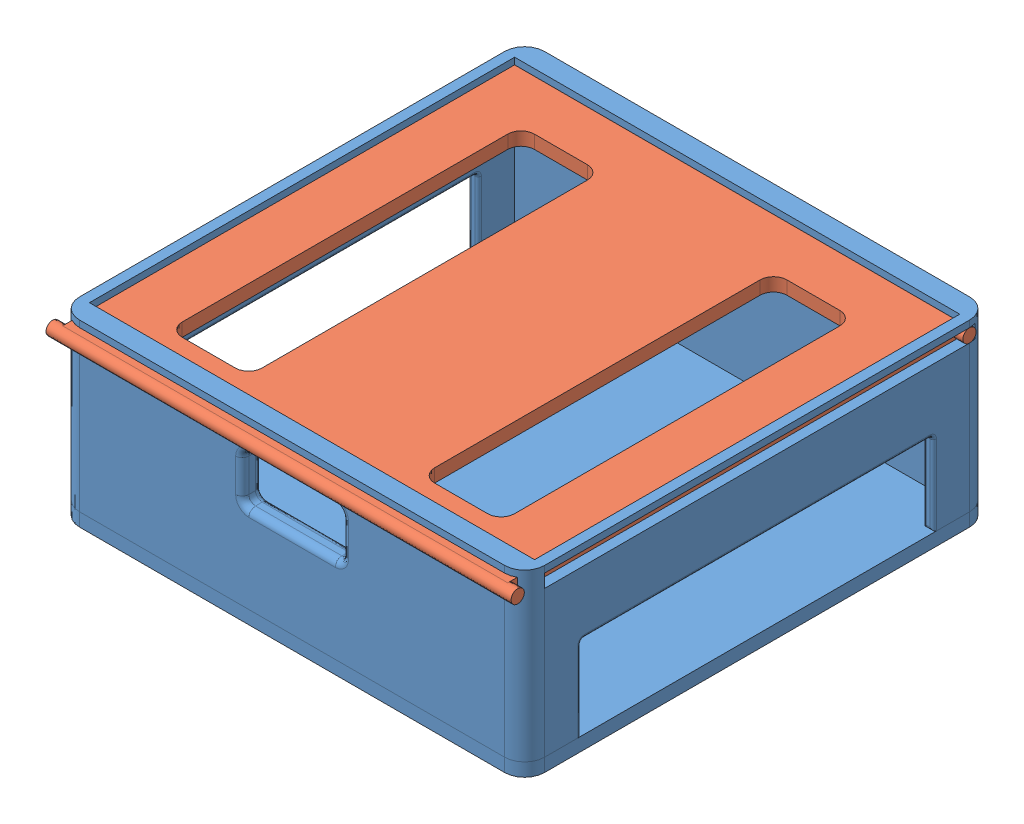
SolidWorks assembly Caja_ESP32, configuration Predeterminado. Lengths in mm.
Overall size (70 27 72.04).
2 component instances, 2 part files, 7 mates.
Components (placement in the parent):
- Caja_ESP32-1: Caja_ESP32 [Predeterminado] at (-4.1994 -8.4591 70) size (70 27 70)
- Slider-1: Slider [Predeterminado] at (-4.1994 14.5409 37.0359) size (70 2 70)
Mates (geometry in assembly coordinates):
- Coincidente1: coincident anti-aligned: plane of Caja_ESP32-1 through (29.3006 16.5409 102) normal (-1 0 0); plane of Slider-1 through (29.3006 13.5409 107.0359) normal (1 0 0)
- Coincidente2: coincident anti-aligned: plane of Caja_ESP32-1 through (-37.6994 16.5409 102) normal (1 0 0); plane of Slider-1 through (-37.6994 13.5409 107.0359) normal (-1 0 0)
- Coincidente9: coincident anti-aligned: plane of Caja_ESP32-1 through (-37.6994 15.5409 37) normal (0 -1 0); plane of Slider-1 through (-37.6994 15.5409 107.0359) normal (0 1 0)
- Coincidente10: coincident anti-aligned: plane of Caja_ESP32-1 through (29.3006 13.5409 37) normal (0 1 0); plane of Slider-1 through (-37.6994 13.5409 107.0359) normal (0 -1 0)
- Tangente1: tangent anti-aligned: plane of Caja_ESP32-1 through (29.3006 13.5409 37) normal (0 1 0); cylinder of Slider-1 through (-37.6994 14.5409 38.0359) axis (-1 0 0) radius 1
- Tangente2: tangent anti-aligned: plane of Caja_ESP32-1 through (29.3006 13.5409 37) normal (0 1 0); cylinder of Slider-1 through (-37.6994 14.5409 38.0359) axis (-1 0 0) radius 1
- Distancia límite1: limit distance = 0.0359 mm: plane of Caja_ESP32-1 through (-4.1994 -8.4591 37) normal (0 0 1); cylinder of Slider-1 through (-37.6994 14.5409 38.0359) axis (-1 0 0) radius 1
